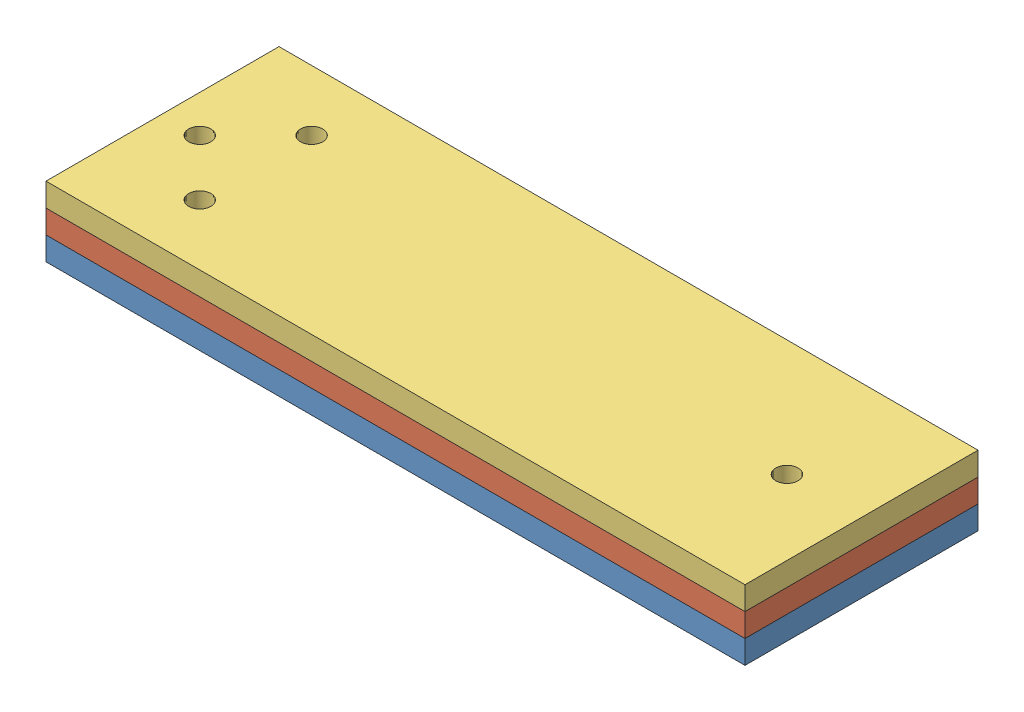
SolidWorks assembly Full, configuration Default. Lengths in mm.
Overall size (75 7.5 25).
3 component instances, 3 part files, 6 mates.
Components (placement in the parent):
- Mid3Ins-1: Mid3Ins [Default] at (31.8899 37.831 55.5534) size (75 2.5 25)
- Sup3Ins-1: Sup3Ins [Default] at (23.4755 42.831 51.3668) size (75 2.5 25)
- Tapa-1: Tapa [Default] at (31.8899 42.831 55.5534) size (75 2.5 25)
Mates (geometry in assembly coordinates):
- Coincident1: coincident aligned: plane of Mid3Ins-1 through (-5.6101 40.331 68.0534) normal (0 0 1); plane of Sup3Ins-1 through (-5.6101 40.331 68.0534) normal (0 0 1)
- Coincident2: coincident aligned: plane of Mid3Ins-1 through (69.3899 40.331 68.0534) normal (1 0 0); plane of Sup3Ins-1 through (69.3899 40.331 43.0534) normal (1 0 0)
- Coincident3: coincident anti-aligned: plane of Mid3Ins-1 through (31.8899 40.331 55.5534) normal (0 1 0); plane of Sup3Ins-1 through (23.4755 40.331 51.3668) normal (0 -1 0)
- Coincident4: coincident aligned: plane of Sup3Ins-1 through (-5.6101 40.331 68.0534) normal (0 0 1); plane of Tapa-1 through (-5.6101 45.331 68.0534) normal (0 0 1)
- Coincident5: coincident aligned: plane of Sup3Ins-1 through (-5.6101 40.331 43.0534) normal (-1 0 0); plane of Tapa-1 through (-5.6101 45.331 68.0534) normal (-1 0 0)
- Coincident6: coincident anti-aligned: plane of Sup3Ins-1 through (23.4755 42.831 51.3668) normal (0 1 0); plane of Tapa-1 through (31.8899 42.831 55.5534) normal (0 -1 0)
